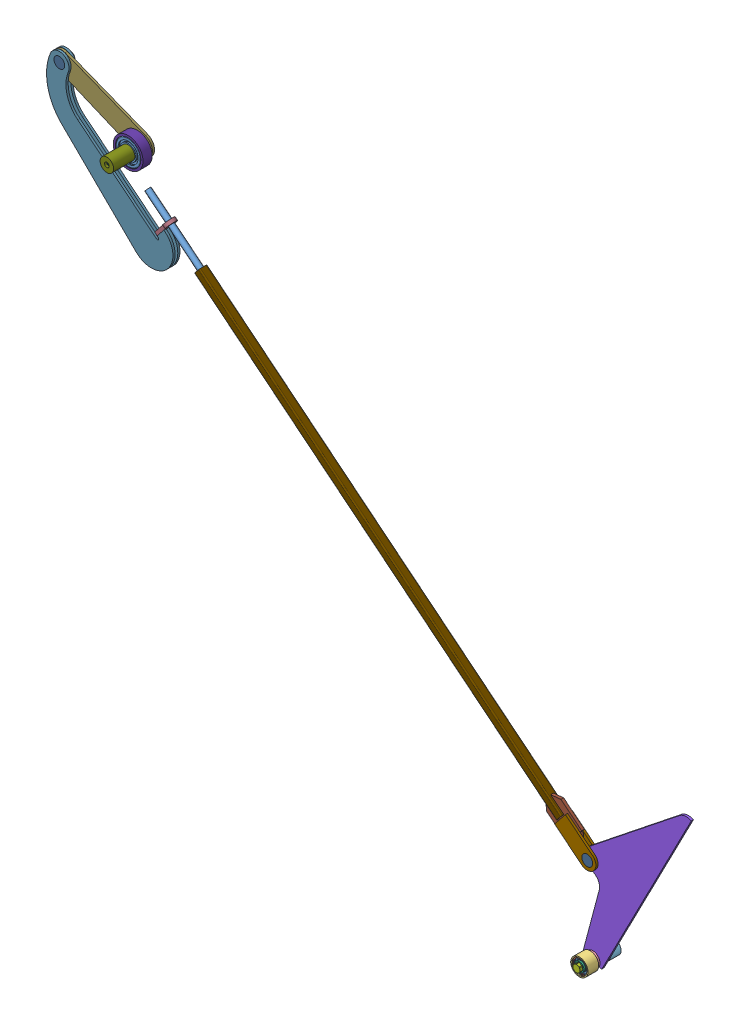
SolidWorks assembly Механизм безопасности, configuration 00. Lengths in mm.
Overall size (1239.94 992.62 931.5).
25 component instances, 21 part files, 68 mates.
Components (placement in the parent):
- Подшипник ГОСТ 8338-75 -1: Подшипник ГОСТ 8338-75  [Подшипник 1000902 ГОСТ 8338-75] at (275.3466 -65 -3.5) x (0 0 1) z (-1 0 0) size (7 28 28)
- Стопор внутренний до 165мм (ГОСТ 13943-86)-1: Стопор внутренний до 165мм (ГОСТ 13943-86) [Кольцо 28] at (275.3466 -65 0) x (0.98609 -0.166215 0) z (0 0 1) size (29.5 30.7 1.2)
- ТП.016.04.02 - Обойма подшипника трапа-1: ТП.016.04.02 - Обойма подшипника трапа [Внешняя] at (275.3466 -65 1.2) x (0 0 -1) z (1 0 0) size (20 32 32)
- ТП.016.04.01 - Палец концевой-1: ТП.016.04.01 - Палец концевой [--] at (275.3466 -65 1.2) x (0 0 -1) z (1 0 0) size (42.3 25 25)
- ТП.016.04.03.03.01.02 - Гайка пальца концевого-1: ТП.016.04.03.03.01.02 - Гайка пальца концевого [--] at (275.3466 -65 -42.3) x (0 0 1) z (-1 0 0) size (20 25 25)
- ТП.016.04.10 - Шайба пальца концевого (3мм)-1: ТП.016.04.10 - Шайба пальца концевого (3мм) [--] at (275.3466 -65 0) x (0 0 -1) z (1 0 0) size (3 17.67 17.67)
- Болты с шестигранной головкой кт.В (ГОСТ 7798-70)-1: Болты с шестигранной головкой кт.В (ГОСТ 7798-70) [Болт М8-6gx65(S13) ГОСТ 7798-77] at (275.3466 -65 3) x (0 0 -1) z (-0.611914 0.790925 0) size (70.3 14.2 13)
- ТП.016.04.03.03.01.01 - Труба оси трапа-1: ТП.016.04.03.03.01.01 - Труба оси трапа [--] at (275.3466 -65 -22.3) x (0 0 -1) z (1 0 0) size (357 27 27)
- ТП.016.04.03.03.02 - Щека трапа (4мм)-1: ТП.016.04.03.03.02 - Щека трапа (4мм) [--] at (275.3466 -65 -22.3) x (0 0 -1) z (1 0 0) size (4 323.68 204.55)
- ТП.016.04.04.04 - Ухо тяги (4мм)-1: ТП.016.04.04.04 - Ухо тяги (4мм) [--] at (269.5391 92.9281 -21.8) x (0.777505 -0.628877 0) z (0 0 1) size (81 32 4)
- ТП.016.04.04.04 - Ухо тяги (4мм)-2: ТП.016.04.04.04 - Ухо тяги (4мм) [--] at (269.5391 92.9281 -30.8) x (0.777505 -0.628877 0) z (0 0 1) size (81 32 4)
- ТП.016.04.08 - Палец тяги-1: ТП.016.04.08 - Палец тяги [--] at (269.5391 92.9281 -17.8) x (0.777505 -0.628877 0) z (0 0 1) size (20 20 21)
- ТП.016.04.04.03 - Проставка уха тяги (5мм)-1: ТП.016.04.04.03 - Проставка уха тяги (5мм) [--] at (219.0012 133.805 -21.8) x (0.777505 -0.628877 0) z (0 0 1) size (72.5 42 5)
- ТП.016.04.06.01 - Рычаг дуги (4мм)-1: ТП.016.04.06.01 - Рычаг дуги (4мм) [--] at (-561.9202 825 -22.3) x (0.926232 -0.376955 0) z (0 0 1) size (198 40 4)
- ТП.016.04.05.01 - Площадка регулировочная (6мм)-1: ТП.016.04.05.01 - Площадка регулировочная (6мм) [--] at (-513.2893 726.1106 -24.3) x (0.777505 -0.628877 0) z (0 0 1) size (6 41.63 19.63)
- ТП.016.04.05.02 - Ухо рычага (4мм)-1: ТП.016.04.05.02 - Ухо рычага (4мм) [Правое] at (-710.1173 885.3128 -21.8) x (0.777505 -0.628877 0) z (0 0 1) size (319.65 109.81 4)
- ТП.016.04.05.02 - Ухо рычага (4мм)-2: ТП.016.04.05.02 - Ухо рычага (4мм) [Правое] at (-710.1173 885.3128 -30.8) x (0.777505 -0.628877 0) z (0 0 1) size (319.65 109.81 4)
- ТП.016.04.08 - Палец тяги-2: ТП.016.04.08 - Палец тяги [--] at (-710.1173 885.3128 -17.8) x (0.933688 -0.358088 0) z (0 0 1) size (20 20 21)
- Подшипник ГОСТ 8338-75 -2: Подшипник ГОСТ 8338-75  [Подшипник 204 ГОСТ 8338-75] at (-561.9202 825 -4.3) x (0 0 -1) z (1 0 0) size (14 47 47)
- ТП.016.04.07.01 - Дуга модель-1: ТП.016.04.07.01 - Дуга модель [--] at (-561.9202 825 7.7) x (0.926232 -0.376955 0) z (0 0 1) size (499.96 27 924)
- ТП.016.04.06.02 - Ось рычага-1: ТП.016.04.06.02 - Ось рычага [--] at (-561.9202 825 -26.3) x (0 0 1) z (-0.926232 0.376955 0) size (64 25 25)
- ТП.016.04.07.02 - Стакан оси рычага-1: ТП.016.04.07.02 - Стакан оси рычага [--] at (-561.9202 825 2.7) x (0 0 -1) z (0.926232 -0.376955 0) size (39.5 25 25)
- ТП.016.01.01.02.02 - Обойма оси рычага-1: ТП.016.01.01.02.02 - Обойма оси рычага [--] at (-561.9202 825 2.7) x (0 0 1) z (-0.926232 0.376955 0) size (17 55 55)
- ТП.016.04.04.01 - Штанга-1: ТП.016.04.04.01 - Штанга [--] at (192.9548 154.8724 -24.3) x (0 0 -1) z (0.777505 -0.628877 0) size (15 15 863.85)
- ТП.016.04.04.02 - Шпилька регулировочная-1: ТП.016.04.04.02 - Шпилька регулировочная [--] at (-454.1989 678.3159 -24.3) x (0 0 -1) z (0.777505 -0.628877 0) size (10 10 151)
Mates (geometry in assembly coordinates):
- Концентричный2: concentric: cylinder of Подшипник ГОСТ 8338-75 -1 through (275.3466 -65 -1003.5) axis (0 0 -1) radius 7.5; circle of assembly
- Совпадение1: coincident: plane of Подшипник ГОСТ 8338-75 -1 through (275.3466 -53.3333 0) normal (0 0 1); circle of assembly
- Совпадение2: coincident: plane of Подшипник ГОСТ 8338-75 -1 through (275.3466 -53.3333 0) normal (0 0 1); plane of Стопор внутренний до 165мм (ГОСТ 13943-86)-1 through (266.4289 -69.8005 0) normal (0 0 -1)
- Концентричный3: concentric: cylinder of Подшипник ГОСТ 8338-75 -1 through (275.3466 -65 -1003.5) axis (0 0 -1) radius 14; cylinder of Стопор внутренний до 165мм (ГОСТ 13943-86)-1 through (275.3466 -65 1.2) axis (0 0 -1) radius 14.75
- Совпадение3: coincident: plane of Стопор внутренний до 165мм (ГОСТ 13943-86)-1 through (266.4289 -69.8005 1.2) normal (0 0 1); plane of ТП.016.04.02 - Обойма подшипника трапа-1 through (275.3466 -65 1.2) normal (0 0 -1)
- Совпадение4: coincident: point of Стопор внутренний до 165мм (ГОСТ 13943-86)-1; plane of ТП.016.04.02 - Обойма подшипника трапа-1 through (275.3466 -65 1.2) normal (0 1 0)
- Совпадение5: coincident: plane of ? through (275.3466 -65 1.2) normal (1 0 0)
- Параллельность1: parallel: plane of ТП.016.04.02 - Обойма подшипника трапа-1 through (275.3466 -65 1.2) normal (1 0 0); plane of assembly through (0 0 0) normal (1 0 0)
- Совпадение6: coordinate: point of ТП.016.04.02 - Обойма подшипника трапа-1; point of ТП.016.04.01 - Палец концевой-1
- Совпадение7: coincident: plane of ТП.016.04.01 - Палец концевой-1 through (275.3466 -65 1.2) normal (1 0 0); plane of ТП.016.04.03.03.01.02 - Гайка пальца концевого-1 through (275.3466 -65 -42.3) normal (-1 0 0)
- Совпадение8: coincident: plane of ТП.016.04.01 - Палец концевой-1 through (275.3466 -65 1.2) normal (0 1 0); plane of ТП.016.04.03.03.01.02 - Гайка пальца концевого-1 through (275.3466 -65 -42.3) normal (0 1 0)
- Совпадение9: coincident: plane of ТП.016.04.01 - Палец концевой-1 through (275.3466 -52.5 -42.3) normal (0 0 -1); plane of ТП.016.04.03.03.01.02 - Гайка пальца концевого-1 through (275.3466 -65 -42.3) normal (0 0 1)
- Совпадение101: coincident: plane of ТП.016.04.03.03.01.02 - Гайка пальца концевого-1 through (275.3466 -65 -42.3) normal (-1 0 0); plane of ТП.016.04.10 - Шайба пальца концевого (3мм)-1 through (275.3466 -65 0) normal (1 0 0)
- Совпадение111: coincident: plane of ТП.016.04.03.03.01.02 - Гайка пальца концевого-1 through (275.3466 -65 -42.3) normal (0 1 0); plane of ТП.016.04.10 - Шайба пальца концевого (3мм)-1 through (275.3466 -65 0) normal (0 1 0)
- Совпадение121: coincident: plane of Подшипник ГОСТ 8338-75 -1 through (275.3466 -57 0) normal (0 0 1); plane of ТП.016.04.10 - Шайба пальца концевого (3мм)-1 through (275.3466 -65 0) normal (0 0 -1)
- Совпадение13: coincident: plane of ТП.016.04.10 - Шайба пальца концевого (3мм)-1 through (275.3466 -65 3) normal (0 0 1); plane of Болты с шестигранной головкой кт.В (ГОСТ 7798-70)-1 through (269.7311 -69.3446 3) normal (0 0 -1)
- Концентричный4: concentric: cylinder of ТП.016.04.01 - Палец концевой-1 through (275.3466 -65 0) axis (0 0 1) radius 4.1; cylinder of Болты с шестигранной головкой кт.В (ГОСТ 7798-70)-1 through (275.3466 -65 1003) axis (0 0 1) radius 4
- Совпадение14: coincident: plane of ТП.016.04.03.03.01.02 - Гайка пальца концевого-1 through (275.3466 -65 -42.3) normal (-1 0 0); plane of ТП.016.04.03.03.01.01 - Труба оси трапа-1 through (275.3466 -65 -22.3) normal (1 0 0)
- Совпадение15: coincident: plane of ТП.016.04.03.03.01.02 - Гайка пальца концевого-1 through (275.3466 -65 -42.3) normal (0 1 0); plane of ТП.016.04.03.03.01.01 - Труба оси трапа-1 through (275.3466 -65 -22.3) normal (0 1 0)
- Расстояние1: distance = 5 mm: plane of ТП.016.04.03.03.01.01 - Труба оси трапа-1 through (275.3466 -65 -22.3) normal (0 0 -1); plane of ТП.016.04.02 - Обойма подшипника трапа-1 through (262.5966 -65 -17.3) normal (0 0 -1)
- Совпадение16: coordinate: point of ТП.016.04.03.03.01.01 - Труба оси трапа-1; point of ТП.016.04.03.03.02 - Щека трапа (4мм)-1
- Расстояние3: distance = 0.5 mm: plane of ТП.016.04.04.04 - Ухо тяги (4мм)-1 through (269.5391 92.9281 -21.8) normal (0 0 1); plane of ТП.016.04.03.03.02 - Щека трапа (4мм)-1 through (448.906 230.705 -22.3) normal (0 0 1)
- Совпадение17: coincident: plane of ТП.016.04.04.04 - Ухо тяги (4мм)-1 through (269.5391 92.9281 -21.8) normal (0.628877 0.777505 0); line of assembly
- Совпадение18: coincident: plane of ТП.016.04.04.04 - Ухо тяги (4мм)-1 through (269.5391 92.9281 -21.8) normal (0.777505 -0.628877 0); point of assembly
- Расстояние4: distance = 5 mm: plane of ТП.016.04.04.04 - Ухо тяги (4мм)-1 through (269.5391 92.9281 -21.8) normal (0 0 -1); plane of ТП.016.04.04.04 - Ухо тяги (4мм)-2 through (269.5391 92.9281 -26.8) normal (0 0 1)
- Концентричный5: concentric: cylinder of ТП.016.04.03.03.02 - Щека трапа (4мм)-1 through (269.5391 92.9281 -26.3) axis (0 0 1) radius 8; cylinder of ТП.016.04.04.04 - Ухо тяги (4мм)-2 through (269.5391 92.9281 -26.8) axis (0 0 -1) radius 8
- Совпадение19: coincident: plane of ТП.016.04.04.04 - Ухо тяги (4мм)-1 through (208.9392 121.365 -17.8) normal (-0.628877 -0.777505 0); plane of ТП.016.04.04.04 - Ухо тяги (4мм)-2 through (208.9392 121.365 -26.8) normal (-0.628877 -0.777505 0)
- Совпадение20: coincident: plane of ТП.016.04.04.04 - Ухо тяги (4мм)-1 through (269.5391 92.9281 -21.8) normal (0.628877 0.777505 0); plane of ТП.016.04.08 - Палец тяги-1 through (269.5391 92.9281 -17.8) normal (0.628877 0.777505 0)
- Совпадение21: coincident: plane of ТП.016.04.04.04 - Ухо тяги (4мм)-1 through (269.5391 92.9281 -21.8) normal (0.777505 -0.628877 0); plane of ТП.016.04.08 - Палец тяги-1 through (269.5391 92.9281 -17.8) normal (0.777505 -0.628877 0)
- Совпадение22: coincident: plane of ТП.016.04.04.04 - Ухо тяги (4мм)-1 through (269.5391 92.9281 -17.8) normal (0 0 1); plane of ТП.016.04.08 - Палец тяги-1 through (269.5391 92.9281 -17.8) normal (0 0 1)
- Совпадение23: coincident: plane of ТП.016.04.04.04 - Ухо тяги (4мм)-1 through (269.5391 92.9281 -21.8) normal (0 0 -1); plane of ТП.016.04.04.03 - Проставка уха тяги (5мм)-1 through (219.0012 133.805 -21.8) normal (0 0 1)
- Совпадение24: coincident: plane of ТП.016.04.04.03 - Проставка уха тяги (5мм)-1 through (219.0012 133.805 -21.8) normal (0.628877 0.777505 0); line of assembly
- Совпадение25: coincident: plane of ТП.016.04.04.04 - Ухо тяги (4мм)-2 through (229.0633 146.2451 -26.8) normal (-0.777505 0.628877 0); plane of ТП.016.04.04.03 - Проставка уха тяги (5мм)-1 through (219.0012 133.805 -21.8) normal (0.777505 -0.628877 0)
- Совпадение122: coincident: plane of ТП.016.04.03.03.02 - Щека трапа (4мм)-1 through (448.906 230.705 -22.3) normal (0 0 1); plane of ТП.016.04.06.01 - Рычаг дуги (4мм)-1 through (-561.9202 825 -22.3) normal (0 0 1)
- Совпадение123: coincident: plane of ТП.016.04.06.01 - Рычаг дуги (4мм)-1 through (-561.9202 825 -22.3) normal (0.376955 0.926232 0); line of assembly
- Совпадение124: coincident: plane of ТП.016.04.06.01 - Рычаг дуги (4мм)-1 through (-561.9202 825 -22.3) normal (0.926232 -0.376955 0); point of assembly
- Совпадение125: coincident: plane of ТП.016.04.05.01 - Площадка регулировочная (6мм)-1 through (-513.2893 726.1106 -24.3) normal (0 0 1); plane of assembly through (0 0 -24.3) normal (0 0 -1)
- Совпадение126: coincident: plane of ТП.016.04.05.01 - Площадка регулировочная (6мм)-1 through (-513.2893 726.1106 -24.3) normal (0.628877 0.777505 0); line of assembly
- Расстояние5: distance = 100 mm: plane of ТП.016.04.05.01 - Площадка регулировочная (6мм)-1 through (-513.2893 726.1106 -24.3) normal (0.777505 -0.628877 0); point of ТП.016.04.06.01 - Рычаг дуги (4мм)-1
- Совпадение128: coincident: plane of ТП.016.04.04.04 - Ухо тяги (4мм)-1 through (269.5391 92.9281 -21.8) normal (0 0 -1); plane of ТП.016.04.05.02 - Ухо рычага (4мм)-1 through (-710.1173 885.3128 -21.8) normal (0 0 1)
- Совпадение129: coincident: plane of ТП.016.04.05.02 - Ухо рычага (4мм)-1 through (-710.1173 885.3128 -21.8) normal (0.628877 0.777505 0); line of assembly
- Совпадение130: coincident: plane of ТП.016.04.05.02 - Ухо рычага (4мм)-1 through (-710.1173 885.3128 -21.8) normal (0.777505 -0.628877 0); point of assembly
- Концентричный6: concentric: cylinder of ТП.016.04.05.02 - Ухо рычага (4мм)-1 through (-710.1173 885.3128 -17.8) axis (0 0 -1) radius 8; cylinder of ТП.016.04.05.02 - Ухо рычага (4мм)-2 through (-710.1173 885.3128 -26.8) axis (0 0 -1) radius 8
- Совпадение131: coincident: plane of ТП.016.04.04.04 - Ухо тяги (4мм)-2 through (269.5391 92.9281 -30.8) normal (0 0 -1); plane of ТП.016.04.05.02 - Ухо рычага (4мм)-2 through (-528.2604 694.0851 -30.8) normal (0 0 -1)
- Совпадение132: coincident: plane of ТП.016.04.05.02 - Ухо рычага (4мм)-1 through (-529.8326 692.1413 -17.8) normal (0.628877 0.777505 0); plane of ТП.016.04.05.02 - Ухо рычага (4мм)-2 through (-529.8326 692.1413 -26.8) normal (0.628877 0.777505 0)
- Концентричный7: concentric: cylinder of ТП.016.04.06.01 - Рычаг дуги (4мм)-1 through (-710.1173 885.3128 -26.3) axis (0 0 1) radius 8; cylinder of ТП.016.04.08 - Палец тяги-2 through (-710.1173 885.3128 982.2) axis (0 0 1) radius 7.75
- Совпадение133: coincident: cone of ТП.016.04.05.02 - Ухо рычага (4мм)-1 through (-710.1173 885.3128 -19.8) axis (0 0 -1); cone of ТП.016.04.08 - Палец тяги-2 through (-710.1173 885.3128 -20.05) axis (0 0 -1)
- Совпадение134: coincident: plane of ТП.016.04.02 - Обойма подшипника трапа-1 through (259.3466 -65 2.7) normal (0 0 1); plane of Подшипник ГОСТ 8338-75 -2 through (-561.9202 843.5 2.7) normal (0 0 1)
- Концентричный8: concentric: cylinder of ТП.016.04.06.01 - Рычаг дуги (4мм)-1 through (-561.9202 825 -26.3) axis (0 0 1) radius 10; cylinder of Подшипник ГОСТ 8338-75 -2 through (-561.9202 825 995.7) axis (0 0 1) radius 10
- Совпадение135: coincident: plane of ТП.016.04.07.01 - Дуга модель-1 through (-561.9202 825 7.7) normal (0.376955 0.926232 0); line of assembly
- Совпадение136: coincident: plane of ТП.016.04.07.01 - Дуга модель-1 through (-561.9202 825 7.7) normal (0.926232 -0.376955 0); point of assembly
- Расстояние6: distance = 5 mm: plane of ТП.016.04.07.01 - Дуга модель-1 through (-561.9202 825 7.7) normal (0 0 1); plane of Подшипник ГОСТ 8338-75 -2 through (-561.9202 843.5 2.7) normal (0 0 1)
- Совпадение137: coincident: plane of ТП.016.04.06.02 - Ось рычага-1 through (-561.9202 825 -26.3) normal (0.376955 0.926232 0); line of assembly
- Совпадение138: coincident: point of Подшипник ГОСТ 8338-75 -2; plane of ТП.016.04.06.02 - Ось рычага-1 through (-561.9202 825 -26.3) normal (-0.926232 0.376955 0)
- Совпадение139: coincident: plane of ТП.016.04.06.01 - Рычаг дуги (4мм)-1 through (-710.1173 885.3128 -26.3) normal (0 0 -1); plane of ТП.016.04.06.02 - Ось рычага-1 through (-561.9202 825 -26.3) normal (0 0 1)
- Совпадение140: coincident: plane of ТП.016.04.06.02 - Ось рычага-1 through (-561.9202 825 -26.3) normal (-0.926232 0.376955 0); plane of ТП.016.04.07.02 - Стакан оси рычага-1 through (-561.9202 825 2.7) normal (0.926232 -0.376955 0)
- Совпадение141: coincident: plane of ТП.016.04.06.02 - Ось рычага-1 through (-561.9202 825 -26.3) normal (0.376955 0.926232 0); plane of ТП.016.04.07.02 - Стакан оси рычага-1 through (-561.9202 825 2.7) normal (0.376955 0.926232 0)
- Совпадение142: coincident: plane of Подшипник ГОСТ 8338-75 -2 through (-561.9202 836.5 2.7) normal (0 0 1); plane of ТП.016.04.07.02 - Стакан оси рычага-1 through (-561.9202 825 2.7) normal (0 0 -1)
- Совпадение143: coincident: plane of ТП.016.04.07.02 - Стакан оси рычага-1 through (-561.9202 825 2.7) normal (0.926232 -0.376955 0); plane of ТП.016.01.01.02.02 - Обойма оси рычага-1 through (-561.9202 825 2.7) normal (-0.926232 0.376955 0)
- Совпадение144: coincident: plane of ТП.016.04.07.02 - Стакан оси рычага-1 through (-561.9202 825 2.7) normal (0.376955 0.926232 0); plane of ТП.016.01.01.02.02 - Обойма оси рычага-1 through (-561.9202 825 2.7) normal (0.376955 0.926232 0)
- Совпадение145: coincident: plane of Подшипник ГОСТ 8338-75 -2 through (-561.9202 836.5 2.7) normal (0 0 1); plane of ТП.016.04.07.02 - Стакан оси рычага-1 through (-561.9202 825 2.7) normal (0 0 -1)
- Совпадение146: coincident: plane of Подшипник ГОСТ 8338-75 -2 through (-561.9202 836.5 2.7) normal (0 0 1); plane of ТП.016.01.01.02.02 - Обойма оси рычага-1 through (-561.9202 825 2.7) normal (0 0 1)
- Совпадение147: coincident: plane of ТП.016.04.04.03 - Проставка уха тяги (5мм)-1 through (197.6714 160.7037 -26.8) normal (-0.777505 0.628877 0); plane of ТП.016.04.04.01 - Штанга-1 through (192.9548 154.8724 -24.3) normal (0.777505 -0.628877 0)
- Совпадение149: coincident: plane of ТП.016.04.04.01 - Штанга-1 through (192.9548 154.8724 -24.3) normal (0 0 -1); plane of assembly through (0 0 -24.3) normal (0 0 -1)
- Совпадение150: coincident: plane of ТП.016.04.04.01 - Штанга-1 through (192.9548 154.8724 -24.3) normal (0.628877 0.777505 0); line of assembly
- Совпадение151: coincident: plane of ТП.016.04.04.01 - Штанга-1 through (-454.1989 678.3159 -24.3) normal (-0.777505 0.628877 0); plane of ТП.016.04.04.02 - Шпилька регулировочная-1 through (-454.1989 678.3159 -24.3) normal (0.777505 -0.628877 0)
- Совпадение152: coincident: plane of ТП.016.04.04.02 - Шпилька регулировочная-1 through (-454.1989 678.3159 -24.3) normal (0 0 -1); plane of assembly through (0 0 -24.3) normal (0 0 -1)
- Совпадение153: coincident: plane of ТП.016.04.04.02 - Шпилька регулировочная-1 through (-454.1989 678.3159 -24.3) normal (0.628877 0.777505 0); line of assembly
